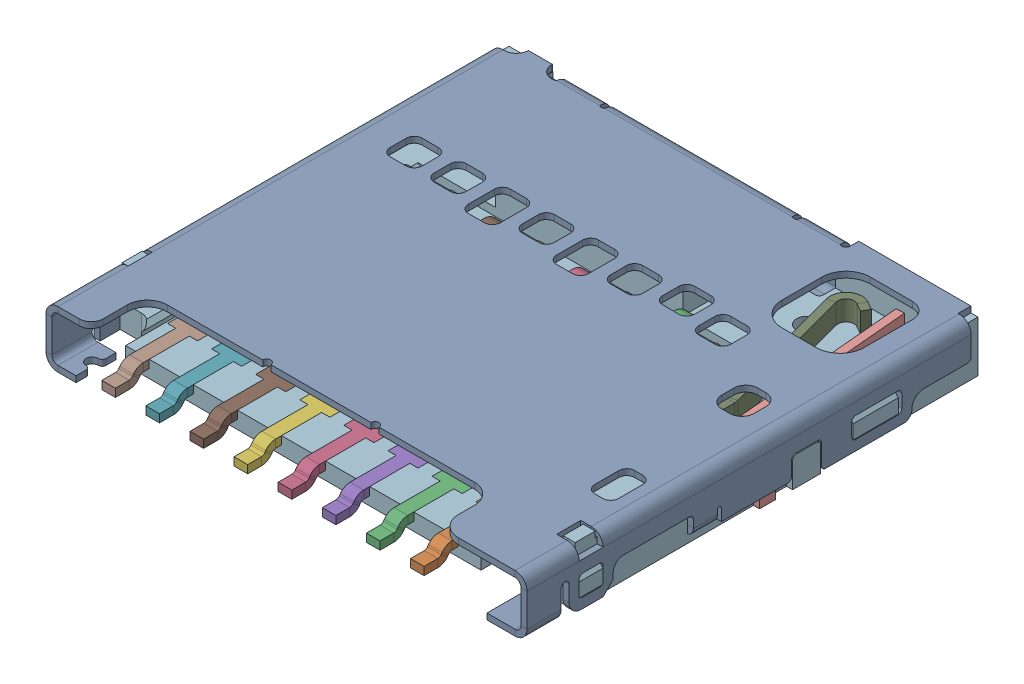
SolidWorks assembly sd_card_slot_molex v11.stp, configuration Default. Lengths in mm.
Overall size (12 1.5 11.41).
14 component instances, 7 part files, 0 mates.
Components (placement in the parent):
- housing.stp-1: housing.stp [Default] at origin size (12 1.43 11.41)
  - shell.stp-1: shell.stp [Default] at origin size (12 1.43 11.41)
- leads.stp-1: leads.stp [Default] at origin size (10.97 1.32 10.44)
  - Component12.stp-1: Component12.stp [Default] at origin size (0.75 1.14 7.86)
  - Component13.stp-1: Component13.stp [Default] at (-1.1 0 0) size (0.75 1.16 8.16)
  - Component14.stp-1: Component14.stp [Default] at (-3.3 0 0) size (0.75 1.13 7.81)
  - Component12.stp-2: Component12.stp [Default] at (-2.2 0 0) size (0.75 1.14 7.86)
  - Component12.stp-3: Component12.stp [Default] at (-4.4 0 0) size (0.75 1.14 7.86)
  - Component12.stp-4: Component12.stp [Default] at (-6.6 0 0) size (0.75 1.14 7.86)
  - Component12.stp-5: Component12.stp [Default] at (-7.7 0 0) size (0.75 1.14 7.86)
  - Component15.stp-1: Component15.stp [Default] at origin size (1.57 1.27 4.5)
  - Component16.stp-1: Component16.stp [Default] at origin size (1.37 1.25 4.89)
  - Component14.stp-2: Component14.stp [Default] at (-5.5 0 0) size (0.75 1.13 7.81)
- base.stp-1: base.stp [Default] at origin size (11.85 1.42 10.4)
